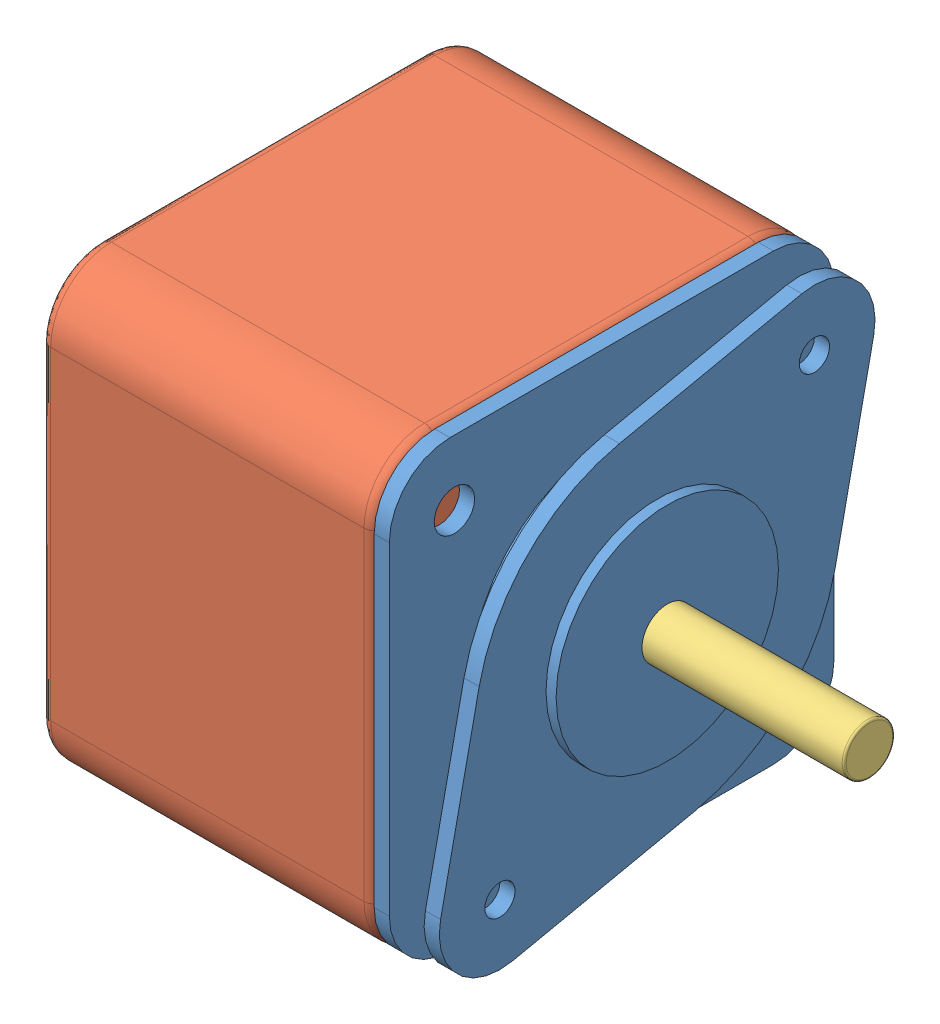
SolidWorks assembly MotorAssem, configuration Default. Lengths in mm.
Overall size (60 44 44).
3 component instances, 3 part files, 5 mates.
Components (placement in the parent):
- Nema17_StepperMotorCap-1: Nema17_StepperMotorCap [Default] at origin size (7 44 44)
- Nema17_StepperMotorCase-1: Nema17_StepperMotorCase [Default] at (-33 0 0) size (33 44 44)
- StepperMotorShaft-1: StepperMotorShaft [Default] at (-33 0 0) x (0 0 -1) z (1 0 0) size (5 5 60)
Mates (geometry in assembly coordinates):
- Coincident1: coincident anti-aligned: plane of Nema17_StepperMotorCap-1 through (0 -16 16) normal (-1 0 0); plane of Nema17_StepperMotorCase-1 through (0 -16 16) normal (1 0 0)
- Coincident2: coincident aligned: plane of Nema17_StepperMotorCap-1 through (1.5 -22 16) normal (0 -1 0); plane of Nema17_StepperMotorCase-1 through (0 -22 16) normal (0 -1 0)
- Coincident3: coincident aligned: plane of Nema17_StepperMotorCap-1 through (1.5 16 22) normal (0 0 1); plane of Nema17_StepperMotorCase-1 through (0 16 22) normal (0 0 1)
- Concentric1: concentric aligned: cylinder of Nema17_StepperMotorCase-1 through (0 0 0) axis (-1 0 0) radius 2.5; cylinder of Part3^Assem1-1 through (27 0 0) axis (-1 0 0) radius 2.5
- Coincident7: coincident aligned: plane of Nema17_StepperMotorCase-1 through (-33 -16 16) normal (-1 0 0); plane of Part3^Assem1-1 through (-33 0 0) normal (-1 0 0)
